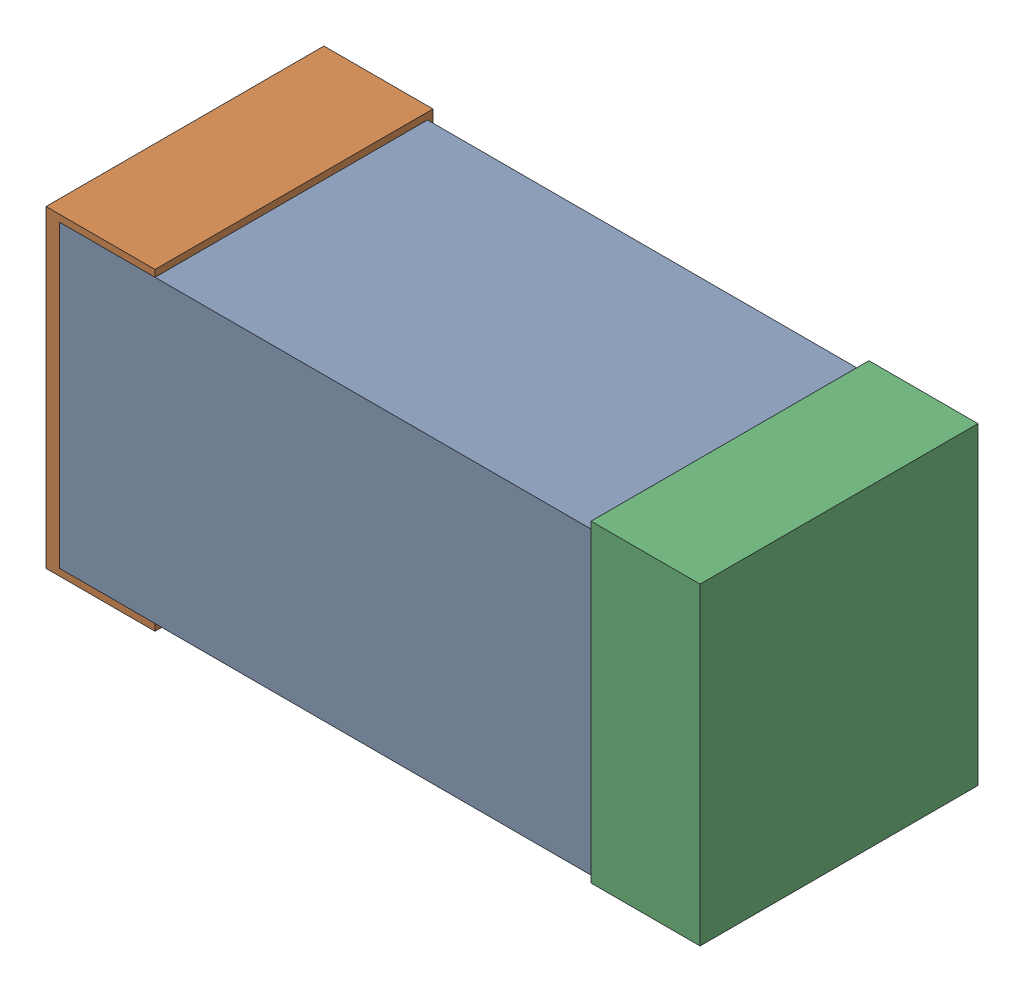
SolidWorks assembly R9, configuration Default. Lengths in mm.
Overall size (1.2 0.58 0.51).
6 component instances, 2 part files, 0 mates.
Components (placement in the parent):
- 384312640-1: 384312640 [Default] at (21.336 38.1 -1.6024) size (1.15 0.55 0.5)
  - Extruded_18-1: Extruded_18 [Default] at origin size (1.15 0.55 0.5)
- 384310976-1: 384310976 [Default] at (20.836 38.1 -1.6124) size (0.2 0.58 0.51)
  - Extruded_19-1: Extruded_19 [Default] at origin size (0.2 0.58 0.51)
- 384310976-2: 384310976 [Default] at (21.836 38.1 -1.6124) size (0.2 0.58 0.51)
  - Extruded_19-1: Extruded_19 [Default] at origin size (0.2 0.58 0.51)
